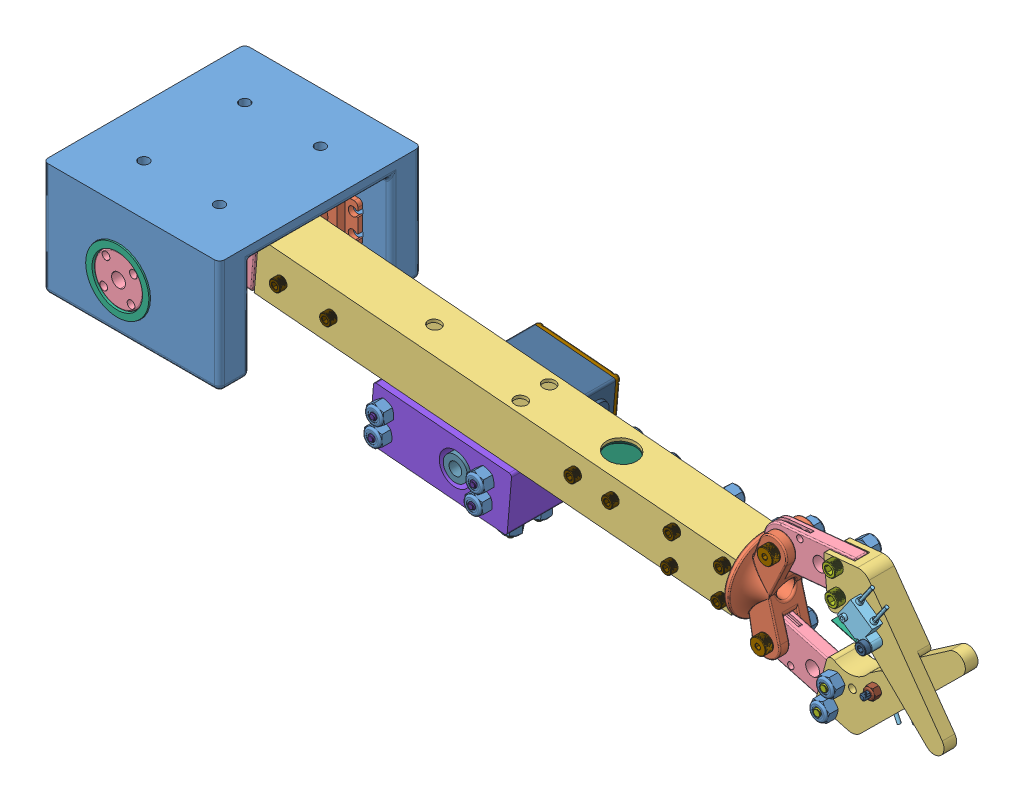
SolidWorks assembly MS-A-0013-03-Gripper, configuration Default. Lengths in mm.
Overall size (408.02 107.05 113.6).
83 component instances, 30 part files, 6 mates.
Components (placement in the parent):
- MS-SA-0013d-03-Gripper Arm-1: MS-SA-0013d-03-Gripper Arm [Default] at (52.2477 10.02 -53.3156) size (306.36 95.81 113.6) (flexible)
  - MS-P-0057-03-Gripper Arm Mount-1: MS-P-0057-03-Gripper Arm Mount [Default] at (-52.2477 40.78 53.3156) x (0 0 1) z (0 1 0) size (101.6 88.9 57.15)
  - MS-SA-0013b-03-Shoulder Servo Mount Assembly-1: MS-SA-0013b-03-Shoulder Servo Mount Assembly [Default] at (2.0387 62.0863 -50.1865) x (0 1 0) z (1 0 0) size (20 43.5 53.2)
    - MS-C-0032-Gripper Shoulder Servo-1: MS-C-0032-Gripper Shoulder Servo [Default] at (-48.0063 17.0406 -6.2663) x (0 0 -1) z (1 0 0) size (53.2 43.5 20)
  - MS-P-0054-03-Box Tubing-1: MS-P-0054-03-Box Tubing [Default] at (11.7132 11.8684 -2.8819) x (0 0 -1) z (0.996386 -0.084946 0) size (25.4 25.4 241.3)
  - MS-P-0058-03-Shoulder L Joint-1: MS-P-0058-03-Shoulder L Joint [Default] at (-14.2277 14.08 -2.1834) x (0 0 -1) z (0.996386 -0.084946 0) size (66.61 26.61 88.65)
  - 525130.step-1: 525130.step [Default] at (-14.2277 14.08 -19.6459) x (0.084946 0.996386 0) z (0.996386 -0.084946 0) size (25.39 6.35 25.39)
  - MS-C-0028-03-Servo Arm Bushing-1: MS-C-0028-03-Servo Arm Bushing [2934T25] at (-14.2277 14.08 34.9006) x (1 0 0) z (0 -1 0) size (38.1 19.05 38.1)
  - 97171A170_ HEAT-SET INSERT FOR PLASTIC_V3-1: 97171A170_ HEAT-SET INSERT FOR PLASTIC_V3 [97171A170] at (19.7723 19.08 -40.131) x (-0.536856 0.843674 0) z (-0.843674 -0.536856 0) size (7.14 9.57 7.14)
  - 97171A170_ HEAT-SET INSERT FOR PLASTIC_V3-2: 97171A170_ HEAT-SET INSERT FOR PLASTIC_V3 [97171A170] at (19.7723 9.08 -40.131) x (-0.383049 0.923728 0) z (-0.923728 -0.383049 0) size (7.14 9.57 7.14)
  - 97171A170_ HEAT-SET INSERT FOR PLASTIC_V3-3: 97171A170_ HEAT-SET INSERT FOR PLASTIC_V3 [97171A170] at (-28.2277 19.08 -40.131) x (-0.940007 -0.341154 0) z (0.341154 -0.940007 0) size (7.14 9.57 7.14)
  - 97171A170_ HEAT-SET INSERT FOR PLASTIC_V3-4: 97171A170_ HEAT-SET INSERT FOR PLASTIC_V3 [97171A170] at (-28.2277 9.08 -40.131) x (-0.231744 0.972777 0) z (-0.972777 -0.231744 0) size (7.14 9.57 7.14)
  - MS-SA-0013a-03-Hand Servo Mount Assembly-1: MS-SA-0013a-03-Hand Servo Mount Assembly [Default] at (51.2821 -52.3342 16.8315) x (0 0 -1) z (0.996386 -0.084946 0) size (72.39 31.33 69.75)
    - MS-P-0055-03 Hand Servo Mount-1: MS-P-0055-03 Hand Servo Mount [Default] at (12.5808 33.9393 61.1705) size (41.76 27.94 69.75)
    - 11886-1: 11886 [Default] at (71.9223 31.717 49.4945) x (0 1 0) z (0 0 1) size (21 45.43 55.5)
      - 11886_bottom-1: 11886_bottom [Default] at (2.2223 -4.2785 0.9275) size (21 2.43 41.5)
      - 11886_middle-1: 11886_middle [Default] at (2.2223 -1.8785 0.9275) size (21 25.7 42.9)
      - 11886_upper-1: 11886_upper [Default] at (6.1473 23.8215 -5.3225) size (21 8.72 55.5)
      - 11886_top-1: 11886_top [Default] at (2.2223 32.5215 0.7275) size (20 8.6 36.5)
    - MS-C-0027-Servo Horn-1: MS-C-0027-Servo Horn [Default] at (34.0008 33.9393 61.172) x (0 0.962595 -0.270945) z (0 0.270945 0.962595) size (25.39 6.35 25.39)
    - MS-P-0060-03-Hand Servo Pulley-1: MS-P-0060-03-Hand Servo Pulley [Default] at (22.8883 33.9393 61.172) x (0 0.270945 0.962595) z (0 -0.962595 0.270945) size (25.4 23.81 25.4)
  - MS-P-0047-Gripper Electromagnet Mount Inside Arm-1: MS-P-0047-Gripper Electromagnet Mount Inside Arm [Default] at (181.776 -4.2234 -2.8819) x (0.996386 -0.084946 0) z (0 0 1) size (31.75 12.7 22.1)
  - 92196A167_18-8 STAINLESS STEEL SOCKET HEAD SCREW-1: 92196A167_18-8 STAINLESS STEEL SOCKET HEAD SCREW [92196A167] at (134.0738 -47.9544 4.2619) x (0.178264 -0.015198 -0.983865) z (-0.084946 -0.996386 0) size (5.73 5.73 42.21)
  - 92196A167_18-8 STAINLESS STEEL SOCKET HEAD SCREW-2: 92196A167_18-8 STAINLESS STEEL SOCKET HEAD SCREW [92196A167] at (134.0738 -47.9544 -10.0256) x (-0.009674 0.000825 -0.999953) z (-0.084946 -0.996386 0) size (5.73 5.73 42.21)
  - 92196A167_18-8 STAINLESS STEEL SOCKET HEAD SCREW-3: 92196A167_18-8 STAINLESS STEEL SOCKET HEAD SCREW [92196A167] at (83.4574 -43.6391 -2.8819) x (-0.22423 0.019117 -0.974349) z (-0.084946 -0.996386 0) size (5.73 5.73 42.21)
  - 92196A169_18-8 STAINLESS STEEL SOCKET HEAD SCREW-7: 92196A169_18-8 STAINLESS STEEL SOCKET HEAD SCREW [92196A169] at (79.5712 -15.6654 19.5306) x (-0.225494 0.974245 0) z (0 0 1) size (5.73 5.73 54.99)
  - 92196A169_18-8 STAINLESS STEEL SOCKET HEAD SCREW-8: 92196A169_18-8 STAINLESS STEEL SOCKET HEAD SCREW [92196A169] at (78.7218 -25.6292 19.5306) x (0.191778 -0.981438 0) z (0 0 1) size (5.73 5.73 54.99)
  - 92196A169_18-8 STAINLESS STEEL SOCKET HEAD SCREW-9: 92196A169_18-8 STAINLESS STEEL SOCKET HEAD SCREW [92196A169] at (130.0864 -19.972 19.5306) x (0.056433 -0.998406 0) z (0 0 1) size (5.73 5.73 54.99)
  - 92196A169_18-8 STAINLESS STEEL SOCKET HEAD SCREW-10: 92196A169_18-8 STAINLESS STEEL SOCKET HEAD SCREW [92196A169] at (129.2369 -29.9359 19.5306) x (-0.049736 -0.998762 0) z (0 0 1) size (5.73 5.73 54.99)
  - 92196A166_18-8 STAINLESS STEEL SOCKET HEAD SCREW-13: 92196A166_18-8 STAINLESS STEEL SOCKET HEAD SCREW [92196A166] at (172.7169 1.6473 -21.9319) x (-0.545077 0.838386 0) z (0 0 -1) size (5.73 5.73 35.83)
  - 92196A166_18-8 STAINLESS STEEL SOCKET HEAD SCREW-15: 92196A166_18-8 STAINLESS STEEL SOCKET HEAD SCREW [92196A166] at (191.6981 0.0291 -21.9319) x (0.89997 0.435952 0) z (0 0 -1) size (5.73 5.73 35.83)
  - 90631A009_LOW-STRENGTH STEEL NYLON-INSERT LOCKNUT-1: 90631A009_LOW-STRENGTH STEEL NYLON-INSERT LOCKNUT [90631A009] at (84.1856 -35.0976 -2.8819) x (-0.834143 0.071114 -0.546944) z (-0.544967 0.046461 0.837169) size (8.73 6.09 10.08)
  - 90631A009_LOW-STRENGTH STEEL NYLON-INSERT LOCKNUT-2: 90631A009_LOW-STRENGTH STEEL NYLON-INSERT LOCKNUT [90631A009] at (134.802 -39.4129 4.2619) x (-0.921899 0.078596 -0.379375) z (-0.378004 0.032227 0.925243) size (8.73 6.09 10.08)
  - 90631A009_LOW-STRENGTH STEEL NYLON-INSERT LOCKNUT-3: 90631A009_LOW-STRENGTH STEEL NYLON-INSERT LOCKNUT [90631A009] at (134.802 -39.4129 -10.0256) x (-0.98171 0.083695 -0.170998) z (-0.17038 0.014526 0.985271) size (8.73 6.09 10.08)
  - 90631A009_LOW-STRENGTH STEEL NYLON-INSERT LOCKNUT-5: 90631A009_LOW-STRENGTH STEEL NYLON-INSERT LOCKNUT [90631A009] at (130.0864 -19.972 12.9931) x (-0.987107 -0.16006 0) z (-0.16006 0.987107 0) size (8.73 6.09 10.08)
  - 90631A009_LOW-STRENGTH STEEL NYLON-INSERT LOCKNUT-7: 90631A009_LOW-STRENGTH STEEL NYLON-INSERT LOCKNUT [90631A009] at (129.2369 -29.9359 12.9931) x (-0.994509 -0.104651 0) z (-0.104651 0.994509 0) size (8.73 6.09 10.08)
  - 90631A009_LOW-STRENGTH STEEL NYLON-INSERT LOCKNUT-9: 90631A009_LOW-STRENGTH STEEL NYLON-INSERT LOCKNUT [90631A009] at (79.5712 -15.6654 12.9931) x (-0.993677 -0.112278 0) z (-0.112278 0.993677 0) size (8.73 6.09 10.08)
  - 90631A009_LOW-STRENGTH STEEL NYLON-INSERT LOCKNUT-11: 90631A009_LOW-STRENGTH STEEL NYLON-INSERT LOCKNUT [90631A009] at (78.7218 -25.6292 12.9931) x (-0.593284 0.804993 0) z (0.804993 0.593284 0) size (8.73 6.09 10.08)
  - 90631A009_LOW-STRENGTH STEEL NYLON-INSERT LOCKNUT-13: 90631A009_LOW-STRENGTH STEEL NYLON-INSERT LOCKNUT [90631A009] at (191.6981 0.0291 -15.5819) x (0.176039 -0.984383 0) z (0.984383 0.176039 0) size (8.73 6.09 10.08)
  - 90631A009_LOW-STRENGTH STEEL NYLON-INSERT LOCKNUT-15: 90631A009_LOW-STRENGTH STEEL NYLON-INSERT LOCKNUT [90631A009] at (172.7169 1.6473 -15.5819) x (0.187204 -0.982321 0) z (0.982321 0.187204 0) size (8.73 6.09 10.08)
  - 92196A166_18-8 STAINLESS STEEL SOCKET HEAD SCREW-17: 92196A166_18-8 STAINLESS STEEL SOCKET HEAD SCREW [92196A166] at (222.6986 1.8473 -21.9319) x (-0.902884 0.429884 0) z (0 0 -1) size (5.73 5.73 35.83)
  - 92196A166_18-8 STAINLESS STEEL SOCKET HEAD SCREW-18: 92196A166_18-8 STAINLESS STEEL SOCKET HEAD SCREW [92196A166] at (248.0068 -0.3104 -21.9319) x (-0.537132 0.843498 0) z (0 0 -1) size (5.73 5.73 35.83)
  - 92196A166_18-8 STAINLESS STEEL SOCKET HEAD SCREW-19: 92196A166_18-8 STAINLESS STEEL SOCKET HEAD SCREW [92196A166] at (221.3501 -13.9703 -21.9319) x (0.278925 0.960313 0) z (0 0 -1) size (5.73 5.73 35.83)
  - 92196A166_18-8 STAINLESS STEEL SOCKET HEAD SCREW-20: 92196A166_18-8 STAINLESS STEEL SOCKET HEAD SCREW [92196A166] at (246.6583 -16.128 -21.9319) x (0.226233 0.974073 0) z (0 0 -1) size (5.73 5.73 35.83)
  - 92196A166_18-8 STAINLESS STEEL SOCKET HEAD SCREW-21: 92196A166_18-8 STAINLESS STEEL SOCKET HEAD SCREW [92196A166] at (24.3673 10.7896 -21.9319) x (0.216747 0.976228 0) z (0 0 -1) size (5.73 5.73 35.83)
  - 92196A166_18-8 STAINLESS STEEL SOCKET HEAD SCREW-22: 92196A166_18-8 STAINLESS STEEL SOCKET HEAD SCREW [92196A166] at (49.6755 8.632 -21.9319) x (0.256336 0.966588 0) z (0 0 -1) size (5.73 5.73 35.83)
  - 90631A009_LOW-STRENGTH STEEL NYLON-INSERT LOCKNUT-16: 90631A009_LOW-STRENGTH STEEL NYLON-INSERT LOCKNUT [90631A009] at (222.6986 1.8473 -15.5819) x (-0.973129 -0.230259 0) z (0.230259 -0.973129 0) size (8.73 6.09 10.08)
  - 90631A009_LOW-STRENGTH STEEL NYLON-INSERT LOCKNUT-17: 90631A009_LOW-STRENGTH STEEL NYLON-INSERT LOCKNUT [90631A009] at (248.0068 -0.3104 -15.5819) x (0.296175 -0.955134 0) z (0.955134 0.296175 0) size (8.73 6.09 10.08)
  - 90631A009_LOW-STRENGTH STEEL NYLON-INSERT LOCKNUT-18: 90631A009_LOW-STRENGTH STEEL NYLON-INSERT LOCKNUT [90631A009] at (221.3501 -13.9703 -15.5819) x (0.383916 -0.923368 0) z (0.923368 0.383916 0) size (8.73 6.09 10.08)
  - 90631A009_LOW-STRENGTH STEEL NYLON-INSERT LOCKNUT-19: 90631A009_LOW-STRENGTH STEEL NYLON-INSERT LOCKNUT [90631A009] at (246.6583 -16.128 -15.5819) x (0.433613 -0.901099 0) z (0.901099 0.433613 0) size (8.73 6.09 10.08)
  - 90631A009_LOW-STRENGTH STEEL NYLON-INSERT LOCKNUT-20: 90631A009_LOW-STRENGTH STEEL NYLON-INSERT LOCKNUT [90631A009] at (49.6755 8.632 -15.5819) x (0.442359 -0.896838 0) z (0.896838 0.442359 0) size (8.73 6.09 10.08)
  - 90631A009_LOW-STRENGTH STEEL NYLON-INSERT LOCKNUT-21: 90631A009_LOW-STRENGTH STEEL NYLON-INSERT LOCKNUT [90631A009] at (24.3673 10.7896 -15.5819) x (-0.457619 0.889148 0) z (-0.889148 -0.457619 0) size (8.73 6.09 10.08)
- MS-SA-0013f-03-03-Center Claw-1: MS-SA-0013f-03-03-Center Claw [Default] at (273.7267 29.4354 -85.9321) x (-0.084946 -0.996386 0) z (0 0 1) size (88.94 137.16 36.64) (flexible)
  - MS-P-0064-03-02 Gripper Center Claw Piece-1: MS-P-0064-03-02 Gripper Center Claw Piece [Default] at (24.6401 45.6335 29.0361) x (0 0 -1) z (1 0 0) size (36.64 54.77 55.37)
  - MS-P-0065-03-02 Gripper Claw v5-1: MS-P-0065-03-02 Gripper Claw v5 [Default] at (8.8403 72.5846 26.0516) x (0 0 -1) z (0.983605 0.180338 0) size (12.7 55.07 65.71)
  - MS-P-0066-03 PVC Pipe-1: MS-P-0066-03 PVC Pipe [Default] at (55.6803 196.6706 -41.6331) x (0.997372 -0.072448 0) z (0 0 1) size (25.4 25.4 127) (hidden)
  - MS-P-0067-03-02 Gripper Claw Base-4: MS-P-0067-03-02 Gripper Claw Base [Default] at (4.0978 45.6335 29.2266) x (-0.983605 -0.180338 0) z (0 0 -1) size (19.05 47.62 6.35)
  - MS-C-0034-Gripper-Limit-Switch-1: MS-C-0034-Gripper-Limit-Switch [Default] at (6.3641 86.548 36.2116) x (0.494102 0.869404 0) z (0 0 -1) size (18.87 29.8 8.3)
    - D2HW_C262M_BASE-1: D2HW_C262M_BASE [Default] at origin size (18.5 26.81 8.3)
    - D2HW_C262M_ACTUATOR-1: D2HW_C262M_ACTUATOR [Default] at (10 3 -2.65) size (13.32 6.3 3.4)
  - MS-P-0067-03-02 Gripper Claw Base-6: MS-P-0067-03-02 Gripper Claw Base [Default] at (45.1823 45.6335 28.8456) x (0.983605 -0.180338 0) z (0 0 1) size (19.05 47.62 6.35)
  - MS-P-0065-03-02 Gripper Claw v5-4: MS-P-0065-03-02 Gripper Claw v5 [Default] at (40.4399 72.5846 32.0206) x (0 0 1) z (-0.983605 0.180338 0) size (12.7 55.07 65.71)
  - 92196A197_18-8 STAINLESS STEEL SOCKET HEAD SCREW-1: 92196A197_18-8 STAINLESS STEEL SOCKET HEAD SCREW [92196A197] at (-7.9196 75.9676 17.1616) x (-0.997184 -0.074988 0) z (0 0 -1) size (6.85 6.85 23.75)
  - 92196A197_18-8 STAINLESS STEEL SOCKET HEAD SCREW-2: 92196A197_18-8 STAINLESS STEEL SOCKET HEAD SCREW [92196A197] at (4.5722 78.2579 17.1616) x (-0.997184 -0.074988 0) z (0 0 -1) size (6.85 6.85 23.75)
  - 90631A009_LOW-STRENGTH STEEL NYLON-INSERT LOCKNUT-1: 90631A009_LOW-STRENGTH STEEL NYLON-INSERT LOCKNUT [90631A009] at (-7.9196 75.9676 23.5116) x (0.949851 -0.312702 0) z (0.312702 0.949851 0) size (8.73 6.09 10.08)
  - 90631A009_LOW-STRENGTH STEEL NYLON-INSERT LOCKNUT-2: 90631A009_LOW-STRENGTH STEEL NYLON-INSERT LOCKNUT [90631A009] at (4.5722 78.2579 23.5116) x (0.951403 -0.307949 0) z (0.307949 0.951403 0) size (8.73 6.09 10.08)
  - 90631A009_LOW-STRENGTH STEEL NYLON-INSERT LOCKNUT-3: 90631A009_LOW-STRENGTH STEEL NYLON-INSERT LOCKNUT [90631A009] at (44.7079 78.2579 34.5606) x (-0.951403 -0.307949 0) z (-0.307949 0.951403 0) size (8.73 6.09 10.08)
  - 90631A009_LOW-STRENGTH STEEL NYLON-INSERT LOCKNUT-4: 90631A009_LOW-STRENGTH STEEL NYLON-INSERT LOCKNUT [90631A009] at (57.1997 75.9676 34.5606) x (-0.949851 -0.312702 0) z (-0.312702 0.949851 0) size (8.73 6.09 10.08)
  - 92196A197_18-8 STAINLESS STEEL SOCKET HEAD SCREW-3: 92196A197_18-8 STAINLESS STEEL SOCKET HEAD SCREW [92196A197] at (44.7079 78.2579 40.9106) x (0.997184 -0.074988 0) z (0 0 1) size (6.85 6.85 23.75)
  - 92196A197_18-8 STAINLESS STEEL SOCKET HEAD SCREW-4: 92196A197_18-8 STAINLESS STEEL SOCKET HEAD SCREW [92196A197] at (57.1997 75.9676 40.9106) x (0.997184 -0.074988 0) z (0 0 1) size (6.85 6.85 23.75)
  - 6389K300_LIGHT DUTY DRY-RUNNING SLEEVE BEARING-1: 6389K300_LIGHT DUTY DRY-RUNNING SLEEVE BEARING [6389K3] at (4.0978 45.6335 29.2266) x (-0.495857 0.868404 0) z (0 0 1) size (7.94 7.94 6.35)
  - 6389K300_LIGHT DUTY DRY-RUNNING SLEEVE BEARING-2: 6389K300_LIGHT DUTY DRY-RUNNING SLEEVE BEARING [6389K3] at (45.1823 45.6335 28.8456) x (-0.984867 0.173311 0) z (0 0 -1) size (7.94 7.94 6.35)
  - 90311A137_316 STAINLESS STEEL THREAD-LOCKING SHOULDER SCREW-1: 90311A137_316 STAINLESS STEEL THREAD-LOCKING SHOULDER SCREW [90311A137] at (4.0978 45.6335 41.3234) x (-0.084946 0.996386 0) z (0 0 1) size (7.94 7.94 25.05)
  - 90311A137_316 STAINLESS STEEL THREAD-LOCKING SHOULDER SCREW-2: 90311A137_316 STAINLESS STEEL THREAD-LOCKING SHOULDER SCREW [90311A137] at (45.1823 45.6335 41.3234) x (-0.241851 0.970313 0) z (0 0 1) size (7.94 7.94 25.05)
  - 90631A009_LOW-STRENGTH STEEL NYLON-INSERT LOCKNUT-5: 90631A009_LOW-STRENGTH STEEL NYLON-INSERT LOCKNUT [90631A009] at (4.0978 45.6335 20.7176) x (0.999998 -0.001774 0) z (0.001774 0.999998 0) size (8.73 6.09 10.08)
  - 90631A009_LOW-STRENGTH STEEL NYLON-INSERT LOCKNUT-7: 90631A009_LOW-STRENGTH STEEL NYLON-INSERT LOCKNUT [90631A009] at (45.1823 45.6335 20.7176) x (0.98763 0.156801 0) z (-0.156801 0.98763 0) size (8.73 6.09 10.08)
  - 91292A020_TYPE 18-8 SS SOCKET HEAD CAP SCREW-1: 91292A020_TYPE 18-8 SS SOCKET HEAD CAP SCREW [91292A020] at (12.7874 97.8502 16.5116) x (0.086557 -0.996247 0) z (0 0 -1) size (5.5 5.5 28.26)
  - 93625A100_18-8 STAINLESS STEEL NYLON-INSERT LOCKNUT-1: 93625A100_18-8 STAINLESS STEEL NYLON-INSERT LOCKNUT [93625A100] at (12.7874 97.8502 23.5116) x (-0.084946 0.996386 0) z (-0.996386 -0.084946 0) size (5.5 4.19 6.35)
  - 93625A100_18-8 STAINLESS STEEL NYLON-INSERT LOCKNUT-2: 93625A100_18-8 STAINLESS STEEL NYLON-INSERT LOCKNUT [93625A100] at (36.4927 97.8502 34.5606) x (0.995999 0.089365 0) z (0.089365 -0.995999 0) size (5.5 4.19 6.35)
  - 91292A020_TYPE 18-8 SS SOCKET HEAD CAP SCREW-2: 91292A020_TYPE 18-8 SS SOCKET HEAD CAP SCREW [91292A020] at (36.4927 97.8502 41.5606) x (-0.996142 -0.087755 0) z (0 0 1) size (5.5 5.5 28.26)
  - MS-C-0034-Gripper-Limit-Switch-2: MS-C-0034-Gripper-Limit-Switch [Default] at (42.916 86.548 21.8606) x (-0.494102 0.869404 0) z (0 0 1) size (18.87 29.8 8.3)
    - D2HW_C262M_BASE-1: D2HW_C262M_BASE [Default] at origin size (18.5 26.81 8.3)
    - D2HW_C262M_ACTUATOR-1: D2HW_C262M_ACTUATOR [Default] at (10 3 -2.65) size (13.32 6.3 3.4)
Mates (geometry in assembly coordinates):
- Coincident5: coincident anti-aligned: plane of MS-SA-0013d-03-Gripper Arm-1/MS-P-0057-03-Gripper Arm Mount-1 through (0 57.15 -101.6) normal (-1 0 0)
- Coincident6: coincident aligned: plane of MS-SA-0013d-03-Gripper Arm-1/MS-P-0057-03-Gripper Arm Mount-1 through (88.9 57.15 0) normal (0 0 1)
- Coincident7: coincident anti-aligned: plane of MS-SA-0013d-03-Gripper Arm-1/MS-P-0057-03-Gripper Arm Mount-1 through (0 0 0) normal (0 -1 0)
- Coincident8: coincident anti-aligned: plane of MS-SA-0013d-03-Gripper Arm-1/MS-P-0054-03-Box Tubing-1 through (305.3327 12.4632 -67.31) normal (0 0 1); plane of MS-SA-0013f-03-03-Center Claw-1/MS-P-0064-03-02 Gripper Center Claw Piece-1 through (269.6493 5.0536 -67.31) normal (0 0 -1)
- Coincident9: coincident anti-aligned: plane of MS-SA-0013d-03-Gripper Arm-1/MS-P-0054-03-Box Tubing-1 through (305.3327 12.4632 -45.085) normal (-0.084946 -0.996386 0); plane of MS-SA-0013f-03-03-Center Claw-1/MS-P-0064-03-02 Gripper Center Claw Piece-1 through (270.5339 15.43 -56.896) normal (0.084946 0.996386 0)
- Coincident10: coincident anti-aligned: plane of MS-SA-0013d-03-Gripper Arm-1/MS-P-0054-03-Box Tubing-1 through (304.3887 1.3909 -56.1975) normal (0.996386 -0.084946 0); plane of MS-SA-0013f-03-03-Center Claw-1/MS-P-0064-03-02 Gripper Center Claw Piece-1 through (305.9503 19.7077 -56.896) normal (-0.996386 0.084946 0)
